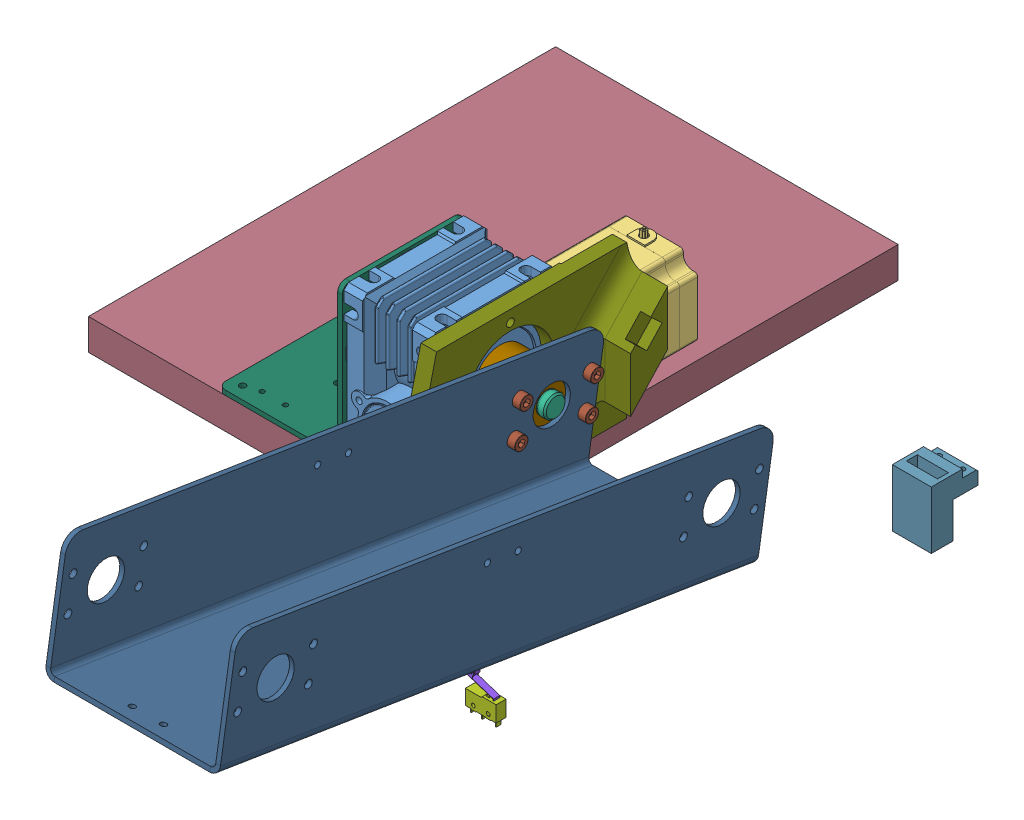
SolidWorks assembly V2.0 SL Rehab Arm main assembly, configuration Default. Lengths in mm.
Overall size (366.5 256.24 582.69).
33 component instances, 16 part files, 33 mates.
Components (placement in the parent):
- mOTOR-1: mOTOR [Default] at (2.9276 0 0) size (63 99.5 171.76)
  - 57HS74..0 .STEP-1: 57HS74..0 .STEP [Default] at origin size (63 99.5 171.76)
    - JMRV030+182________9__.STEP.STEP-1: JMRV030+182________9__.STEP.STEP [Default] at (107.0724 75.4426 266.1235) x (0 0 -1) z (-1 0 0) size (95.75 99.5 63)
      - JMRV030__9__.STEP.STEP-1: JMRV030__9__.STEP.STEP [Default] at (37.8735 8.9192 110) size (90.75 97 63)
      - F30-182______.STEP.STEP-1: F30-182______.STEP.STEP [Default] at (31.8735 8.9192 110) size (20 59 59)
    - 57HS7407-23J3-500.STEP-1: 57HS7407-23J3-500.STEP [Default] at (-2.9276 66.5235 138.25) size (56.4 61.4 99.01)
    - cross recessed pan head screws gb_GB_CROSS_SCREWS_TYPE1 M3X30-30  H type-N.STEP-1: cross recessed pan head screws gb_GB_CROSS_SCREWS_TYPE1 M3X30-30  H type-N.STEP [Default] at (-28.4276 50.5235 214.15) x (0 0 -1) z (1 0 0) size (32.39 5.6 5.6)
    - cross recessed pan head screws gb_GB_CROSS_SCREWS_TYPE1 M3X30-30  H type-N.STEP-2: cross recessed pan head screws gb_GB_CROSS_SCREWS_TYPE1 M3X30-30  H type-N.STEP [Default] at (-28.4276 82.5235 214.15) x (0 0 -1) z (1 0 0) size (32.39 5.6 5.6)
    - cross recessed pan head screws gb_GB_CROSS_SCREWS_TYPE1 M3X30-30  H type-N.STEP-3: cross recessed pan head screws gb_GB_CROSS_SCREWS_TYPE1 M3X30-30  H type-N.STEP [Default] at (22.5724 50.5235 214.15) x (0 0 -1) z (1 0 0) size (32.39 5.6 5.6)
    - cross recessed pan head screws gb_GB_CROSS_SCREWS_TYPE1 M3X30-30  H type-N.STEP-4: cross recessed pan head screws gb_GB_CROSS_SCREWS_TYPE1 M3X30-30  H type-N.STEP [Default] at (22.5724 82.5235 214.15) x (0 0 -1) z (1 0 0) size (32.39 5.6 5.6)
    - hexagon socket head cap screws gb_GB_FASTENER_SCREWS_HSHCS M4X6-N.STEP-1: hexagon socket head cap screws gb_GB_FASTENER_SCREWS_HSHCS M4X6-N.STEP [Default] at (20.6574 90.1085 205.45) x (0 0 1) z (-1 0 0) size (10 7 7)
    - hexagon socket head cap screws gb_GB_FASTENER_SCREWS_HSHCS M4X6-N.STEP-2: hexagon socket head cap screws gb_GB_FASTENER_SCREWS_HSHCS M4X6-N.STEP [Default] at (-26.5126 90.1085 205.45) x (0 0 1) z (-1 0 0) size (10 7 7)
    - hexagon socket head cap screws gb_GB_FASTENER_SCREWS_HSHCS M4X6-N.STEP-3: hexagon socket head cap screws gb_GB_FASTENER_SCREWS_HSHCS M4X6-N.STEP [Default] at (20.6574 42.9385 205.45) x (0 0 1) z (-1 0 0) size (10 7 7)
    - hexagon socket head cap screws gb_GB_FASTENER_SCREWS_HSHCS M4X6-N.STEP-4: hexagon socket head cap screws gb_GB_FASTENER_SCREWS_HSHCS M4X6-N.STEP [Default] at (-26.5126 42.9385 205.45) x (0 0 1) z (-1 0 0) size (10 7 7)
- CNC Shaft-1: CNC Shaft [Default] at (0 96.5235 269.25) x (1 0 0) z (0 -0.840589 0.541674) size (122 14 14)
- SS_5GL2-1: SS_5GL2 [Default] at (61.5859 -49.3889 312.45) x (-1 0 0) z (0 0 -1) size (20.22 25.7 6.4)
  - SS_5GL2_BASE-1: SS_5GL2_BASE [Default] at origin size (19.8 15.06 6.4)
  - SS_5GL2_ACTUATOR-1: SS_5GL2_ACTUATOR [Default] at (-11.5 7.7 0) size (17.42 11.6 5.4)
- Arm rest sheet metal-1: Arm rest sheet metal [Default] at (32.5 96.5235 269.25) x (1 0 0) z (0 0.158212 0.987405) size (142 75 350)
  - Shaft arm CNC-1: Shaft arm CNC [Default] at origin size (30 35 60)
  - 1xArm rester sheet metal-1: 1xArm rester sheet metal [Default] at (86 -39.5 320) x (0 0 1) z (-1 0 0) size (350 75 112)
- socket head cap screw_iso-2: socket head cap screw_iso [ISO 4762 M5 x 20 - 20N] at (70.5 110.5301 290.2991) x (-1 0 0) z (0 0.924225 0.381849) size (25 8.5 8.5)
- socket head cap screw_iso-3: socket head cap screw_iso [ISO 4762 M5 x 20 - 20N] at (70.5 82.5168 248.2009) x (-1 0 0) z (0 0.924225 0.381849) size (25 8.5 8.5)
- socket head cap screw_iso-4: socket head cap screw_iso [ISO 4762 M5 x 20 - 20N] at (70.5 89.7946 293.6215) x (-1 0 0) z (0 0.924225 0.381849) size (25 8.5 8.5)
- socket head cap screw_iso-5: socket head cap screw_iso [ISO 4762 M5 x 20 - 20N] at (70.5 103.2523 244.8785) x (-1 0 0) z (0 0.924225 0.381849) size (25 8.5 8.5)
- torque nut 01_iso-2: torque nut 01_iso [ISO 7040-M5-N] at (48.1 110.5301 290.2991) x (0 0 1) z (-1 0 0) size (8 9.24 6.8)
- torque nut 01_iso-3: torque nut 01_iso [ISO 7040-M5-N] at (48.1 103.2523 244.8785) x (0 0 1) z (-1 0 0) size (8 9.24 6.8)
- torque nut 01_iso-4: torque nut 01_iso [ISO 7040-M5-N] at (48.1 89.7946 293.6215) x (0 0 1) z (-1 0 0) size (8 9.24 6.8)
- torque nut 01_iso-5: torque nut 01_iso [ISO 7040-M5-N] at (48.1 82.5168 248.2009) x (0 0 1) z (-1 0 0) size (8 9.24 6.8)
- Wood block-1: Wood block [Default] at (-82 17.0235 159.25) size (220 20 300)
- 3D print limit switch holder-1: 3D print limit switch holder [Default] at (84 -54 26.5) x (0 0 1) z (-1 0 0) size (30 37 25)
- 2xservice learning Motor Mount Sheet Metal-4: 2xservice learning Motor Mount Sheet Metal [Default] at (-32 37.0235 229.25) x (-1 0 0) z (0 0 -1) size (80 98.5 80)
- limit switch parts-1: limit switch parts [Default] at (29 96.5235 269.25) size (50 98 142.1)
Mates (geometry in assembly coordinates):
- Coincident3: coincident anti-aligned: plane of mOTOR-1 through (0 0 0) normal (-1 0 0)
- Concentric2: concentric aligned: cylinder of mOTOR-1/57HS74..0 .STEP-1/JMRV030+182________9__.STEP.STEP-1/JMRV030__9__.STEP.STEP-1 through (0 96.5235 269.25) axis (-1 0 0) radius 7; cylinder of CNC Shaft-1 through (34 96.5235 269.25) axis (-1 0 0) radius 7
- Coincident6: coincident aligned: plane of CNC Shaft-1 through (0 96.5235 269.25) normal (1 0 0)
- Concentric3: concentric anti-aligned: cylinder of CNC Shaft-1 through (34 96.5235 269.25) axis (-1 0 0) radius 7; cylinder of Arm rest sheet metal-1/Shaft arm CNC-1 through (32.5 96.5235 269.25) axis (1 0 0) radius 7
- Concentric4: concentric anti-aligned: cylinder of Arm rest sheet metal-1/1xArm rester sheet metal-1 through (62.5 110.5301 290.2991) axis (-1 0 0) radius 2.5; cylinder of socket head cap screw_iso-2 through (102.25 110.5301 290.2991) axis (1 0 0) radius 4.25
- Coincident8: coincident anti-aligned: plane of Arm rest sheet metal-1/1xArm rester sheet metal-1 through (65.5 108.1486 591.469) normal (1 0 0); plane of socket head cap screw_iso-2 through (65.5 108.9072 294.2271) normal (-1 0 0)
- Concentric5: concentric anti-aligned: cylinder of Arm rest sheet metal-1/1xArm rester sheet metal-1 through (62.5 82.5168 248.2009) axis (-1 0 0) radius 2.5; cylinder of socket head cap screw_iso-3 through (102.25 82.5168 248.2009) axis (1 0 0) radius 4.25
- Coincident9: coincident anti-aligned: plane of Arm rest sheet metal-1/1xArm rester sheet metal-1 through (65.5 108.1486 591.469) normal (1 0 0); plane of socket head cap screw_iso-3 through (65.5 80.894 252.1289) normal (-1 0 0)
- Concentric6: concentric anti-aligned: cylinder of Arm rest sheet metal-1/1xArm rester sheet metal-1 through (62.5 89.7946 293.6215) axis (-1 0 0) radius 2.5; cylinder of socket head cap screw_iso-4 through (102.25 89.7946 293.6215) axis (1 0 0) radius 4.25
- Coincident10: coincident anti-aligned: plane of Arm rest sheet metal-1/1xArm rester sheet metal-1 through (65.5 108.1486 591.469) normal (1 0 0); plane of socket head cap screw_iso-4 through (65.5 88.1717 297.5495) normal (-1 0 0)
- Concentric7: concentric anti-aligned: cylinder of Arm rest sheet metal-1/1xArm rester sheet metal-1 through (62.5 103.2523 244.8785) axis (-1 0 0) radius 2.5; cylinder of socket head cap screw_iso-5 through (102.25 103.2523 244.8785) axis (1 0 0) radius 4.25
- Coincident11: coincident anti-aligned: plane of Arm rest sheet metal-1/1xArm rester sheet metal-1 through (65.5 108.1486 591.469) normal (1 0 0); plane of socket head cap screw_iso-5 through (65.5 101.6295 248.8064) normal (-1 0 0)
- Concentric8: concentric aligned: cylinder of Arm rest sheet metal-1/Shaft arm CNC-1 through (32.5 110.5301 290.2991) axis (-1 0 0) radius 2.5; cylinder of torque nut 01_iso-2 through (73.1375 110.5301 290.2991) axis (-1 0 0) radius 2.5
- Coincident12: coincident anti-aligned: plane of Arm rest sheet metal-1/Shaft arm CNC-1 through (52.5 96.5235 269.25) normal (-1 0 0); plane of torque nut 01_iso-2 through (52.5 115.1489 290.2991) normal (1 0 0)
- Concentric9: concentric aligned: cylinder of Arm rest sheet metal-1/Shaft arm CNC-1 through (32.5 103.2523 244.8785) axis (-1 0 0) radius 2.5; cylinder of torque nut 01_iso-3 through (73.1375 103.2523 244.8785) axis (-1 0 0) radius 2.5
- Coincident13: coincident anti-aligned: plane of Arm rest sheet metal-1/Shaft arm CNC-1 through (52.5 96.5235 269.25) normal (-1 0 0); plane of torque nut 01_iso-3 through (52.5 107.8711 244.8785) normal (1 0 0)
- Concentric10: concentric aligned: cylinder of Arm rest sheet metal-1/Shaft arm CNC-1 through (32.5 89.7946 293.6215) axis (-1 0 0) radius 2.5; cylinder of torque nut 01_iso-4 through (73.1375 89.7946 293.6215) axis (-1 0 0) radius 2.5
- Coincident14: coincident anti-aligned: plane of Arm rest sheet metal-1/Shaft arm CNC-1 through (52.5 96.5235 269.25) normal (-1 0 0); plane of torque nut 01_iso-4 through (52.5 94.4134 293.6215) normal (1 0 0)
- Concentric11: concentric aligned: cylinder of Arm rest sheet metal-1/Shaft arm CNC-1 through (32.5 82.5168 248.2009) axis (-1 0 0) radius 2.5; cylinder of torque nut 01_iso-5 through (73.1375 82.5168 248.2009) axis (-1 0 0) radius 2.5
- Coincident15: coincident anti-aligned: plane of Arm rest sheet metal-1/Shaft arm CNC-1 through (52.5 96.5235 269.25) normal (-1 0 0); plane of torque nut 01_iso-5 through (52.5 87.1356 248.2009) normal (1 0 0)
- Coincident16: coincident aligned: plane of CNC Shaft-1 through (62.5 100.112 274.8189) normal (1 0 0); plane of Arm rest sheet metal-1/Shaft arm CNC-1 through (62.5 96.5235 269.25) normal (1 0 0)
- Coincident20: coincident anti-aligned: plane of SS_5GL2-1/SS_5GL2_BASE-1 through (56.3859 -51.8889 309.25) normal (0 0 -1); plane of Wood block-1 through (28 37.0235 309.25) normal (0 0 1)
- Coincident23: coincident anti-aligned: plane of mOTOR-1/57HS74..0 .STEP-1/JMRV030+182________9__.STEP.STEP-1/JMRV030__9__.STEP.STEP-1 through (-29 99.9468 304.75) normal (-1 0 0); plane of 2xservice learning Motor Mount Sheet Metal-4 through (-29 37.0235 229.25) normal (1 0 0)
- Concentric12: concentric aligned: cylinder of mOTOR-1/57HS74..0 .STEP-1/JMRV030+182________9__.STEP.STEP-1/JMRV030__9__.STEP.STEP-1 through (-31.5 96.5235 269.25) axis (-1 0 0) radius 27.5; cylinder of 2xservice learning Motor Mount Sheet Metal-4 through (-29 96.5235 269.25) axis (-1 0 0) radius 28
- Parallel1: parallel aligned: plane of 2xservice learning Motor Mount Sheet Metal-4 through (-32 37.0235 229.25) normal (0 1 0)
- Coincident24: coincident aligned: plane of mOTOR-1 through (2.9276 0 0) normal (0 1 0)
- Coincident25: coincident aligned: plane of mOTOR-1 through (2.9276 0 0) normal (0 0 1)
- Coincident26: coincident anti-aligned: plane of Wood block-1 through (-82 37.0235 159.25) normal (0 1 0); plane of 2xservice learning Motor Mount Sheet Metal-4 through (-32 37.0235 229.25) normal (0 -1 0)
- Coincident27: coincident aligned: plane of Wood block-1 through (28 37.0235 309.25) normal (0 0 1); plane of 2xservice learning Motor Mount Sheet Metal-4 through (-109 37.0235 309.25) normal (0 0 1)
- Coincident28: coincident aligned: plane of mOTOR-1/57HS74..0 .STEP-1/JMRV030+182________9__.STEP.STEP-1/JMRV030__9__.STEP.STEP-1 through (28 39.5235 309.25) normal (1 0 0); plane of Wood block-1 through (28 37.0235 309.25) normal (1 0 0)
- Coincident29: coincident anti-aligned: plane of mOTOR-1/57HS74..0 .STEP-1/JMRV030+182________9__.STEP.STEP-1/JMRV030__9__.STEP.STEP-1 through (29 99.9468 304.75) normal (1 0 0); plane of limit switch parts-1 through (29 96.5235 269.25) normal (-1 0 0)
- Concentric13: concentric anti-aligned: cylinder of mOTOR-1/57HS74..0 .STEP-1/JMRV030+182________9__.STEP.STEP-1/JMRV030__9__.STEP.STEP-1 through (31.5 96.5235 269.25) axis (1 0 0) radius 27.5; cylinder of limit switch parts-1 through (39 96.5235 269.25) axis (-1 0 0) radius 28
- Concentric14: concentric anti-aligned: cylinder of mOTOR-1/57HS74..0 .STEP-1/JMRV030+182________9__.STEP.STEP-1/JMRV030__9__.STEP.STEP-1 through (29 64.0235 269.25) axis (-1 0 0) radius 2.5; cylinder of limit switch parts-1 through (39 64.0235 269.25) axis (1 0 0) radius 2.5
